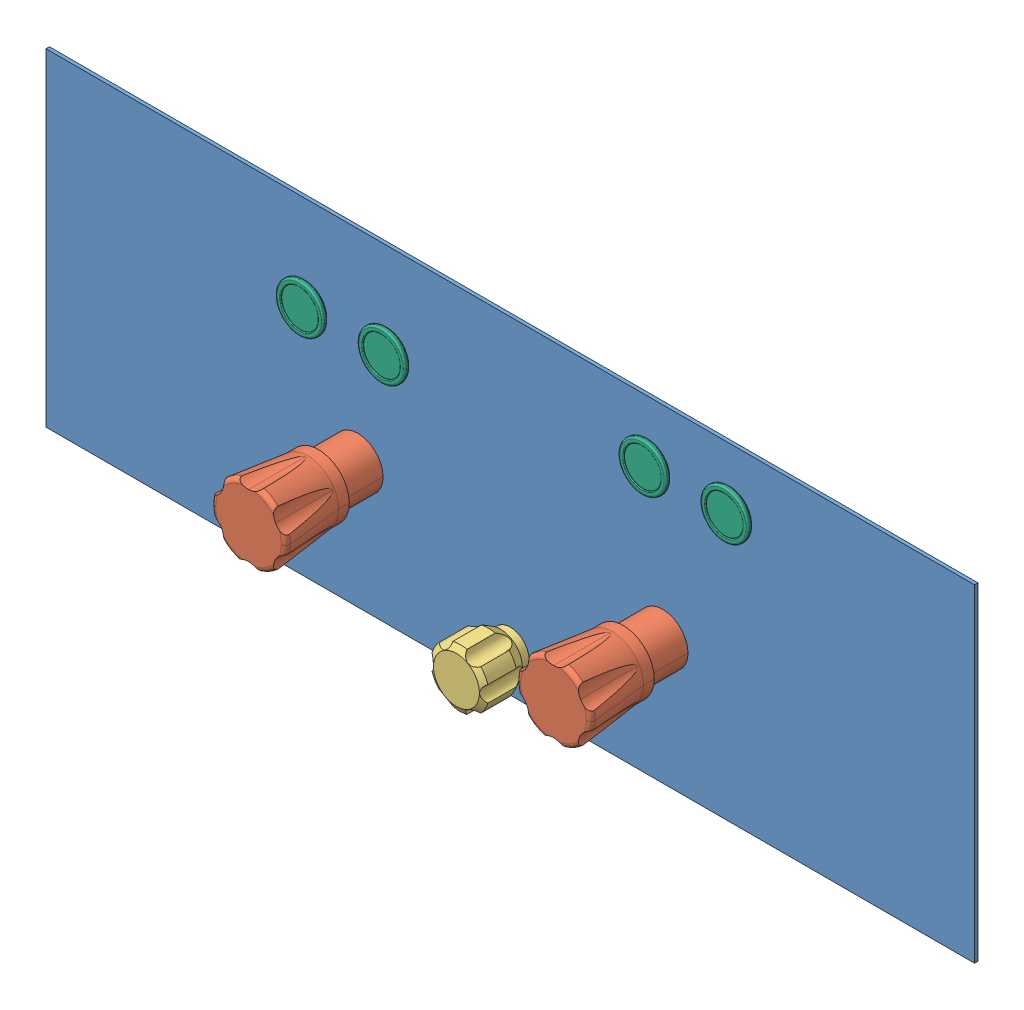
SolidWorks assembly N2_node, configuration Default. Lengths in mm.
Overall size (863.6 304.8 263.66).
11 component instances, 6 part files, 17 mates.
Components (placement in the parent):
- Pressure_panel-1: Pressure_panel [Default] at origin size (863.6 304.8 3.17)
- PRV-1&2_RSHN4-02-6-VVK-Swagelok-1: PRV-1&2_RSHN4-02-6-VVK-Swagelok [Default] at (334.7462 82.8227 -125.3) size (72 78.02 230.14)
- PRV-1&2_RSHN4-02-6-VVK-Swagelok-2: PRV-1&2_RSHN4-02-6-VVK-Swagelok [Default] at (51.1462 82.8227 -125.3) size (72 78.02 230.14)
- KCY1JPA412A20000_PRT_29-1: KCY1JPA412A20000_PRT_29 [Default] at (192.9462 3.5881 -158.828) x (0 1 0) z (0 0 1) size (56.39 55.88 212.09)
- SS-2650-08-08-08-08-1: SS-2650-08-08-08-08 [5482K249] at (192.9462 82.8227 -72.214) size (61.9 61.9 22)
- SS-2404-08-08-1: SS-2404-08-08 [5482K114] at (93.3616 82.8227 -72.214) x (1 0 0) z (0 0.999804 0.019774) size (38.48 23.83 20.64)
- SS-2404-08-08-2: SS-2404-08-08 [5482K114] at (292.5308 82.8227 -72.214) x (-1 0 0) z (0 -0.116154 -0.993231) size (38.48 23.83 20.64)
- 9780T219_VIBRATION-RESISTANT PRESSURE GAUGE-1: 9780T219_VIBRATION-RESISTANT PRESSURE GAUGE [9780T219] at (2.0529 184.7975 8.636) x (0.999997 0.002285 0) z (0 0 1) size (44.45 61.91 48.07)
- 9780T219_VIBRATION-RESISTANT PRESSURE GAUGE-3: 9780T219_VIBRATION-RESISTANT PRESSURE GAUGE [9780T219] at (320.8697 216.2141 8.636) x (-0.158074 0.987427 0) z (0 0 1) size (44.45 61.91 48.07)
- 9780T219_VIBRATION-RESISTANT PRESSURE GAUGE-2: 9780T219_VIBRATION-RESISTANT PRESSURE GAUGE [9780T219] at (78.2529 184.7975 8.636) x (0.999997 0.002285 0) z (0 0 1) size (44.45 61.91 48.07)
- 9780T219_VIBRATION-RESISTANT PRESSURE GAUGE-4: 9780T219_VIBRATION-RESISTANT PRESSURE GAUGE [9780T219] at (397.0697 216.2141 8.636) x (-0.158074 0.987427 0) z (0 0 1) size (44.45 61.91 48.07)
Mates (geometry in assembly coordinates):
- Distance1: distance = 25.4 mm anti-aligned: plane of Pressure_panel-1 through (0 0 0) normal (0 0 -1); plane of PRV-1&2_RSHN4-02-6-VVK-Swagelok-1 through (334.7462 82.8227 -25.4) normal (0 0 1)
- Parallel6: parallel: line of Pressure_panel-1 through (304.8 -238.8538 271.0227) axis (0 0 -1); plane of PRV-1&2_RSHN4-02-6-VVK-Swagelok-1 through (298.7462 82.8227 -0.088) normal (-1 0 0)
- Parallel7: parallel aligned: plane of Pressure_panel-1 through (-238.8538 271.0227 3.175) normal (-1 0 0); plane of PRV-1&2_RSHN4-02-6-VVK-Swagelok-2 through (15.1462 82.8227 -0.088) normal (-1 0 0)
- Distance3: distance = 254 mm aligned: plane of PRV-1&2_RSHN4-02-6-VVK-Swagelok-2 through (15.1462 82.8227 -0.088) normal (-1 0 0); plane of Pressure_panel-1 through (-238.8538 271.0227 3.175) normal (-1 0 0)
- Distance4: distance = 254 mm aligned: plane of PRV-1&2_RSHN4-02-6-VVK-Swagelok-1 through (370.7462 82.8227 -0.088) normal (1 0 0); plane of Pressure_panel-1 through (624.7462 271.0227 3.175) normal (1 0 0)
- Concentric1: concentric anti-aligned: cone of PRV-1&2_RSHN4-02-6-VVK-Swagelok-1 through (306.2575 82.8227 -72.214) axis (1 0 0); cylinder of SS-2650-08-08-08-08-1 through (223.8961 82.8227 -72.214) axis (-1 0 0) radius 4.9657
- Concentric5: concentric aligned: cone of KCY1JPA412A20000_PRT_29-1 through (192.9462 27.4411 -72.214) axis (0 -1 0); cylinder of SS-2650-08-08-08-08-1 through (192.9462 113.7726 -72.214) axis (0 -1 0) radius 4.9657
- Parallel10: parallel aligned: plane of Pressure_panel-1 through (0 0 3.175) normal (0 0 1); plane of KCY1JPA412A20000_PRT_29-1 through (192.9462 14.2881 53.262) normal (0 0 1)
- Concentric7: concentric aligned: cone of PRV-1&2_RSHN4-02-6-VVK-Swagelok-2 through (79.6349 82.8227 -72.214) axis (-1 0 0); cylinder of SS-2650-08-08-08-08-1 through (223.8961 82.8227 -72.214) axis (-1 0 0) radius 4.9657
- Concentric8: concentric anti-aligned: cone of PRV-1&2_RSHN4-02-6-VVK-Swagelok-2 through (79.6349 82.8227 -72.214) axis (-1 0 0); cylinder of SS-2404-08-08-1 through (112.4116 82.8227 -72.214) axis (1 0 0) radius 4.9657
- Coincident18: coincident anti-aligned: plane of PRV-1&2_RSHN4-02-6-VVK-Swagelok-2 through (87.1462 82.8227 -0.088) normal (1 0 0); plane of SS-2404-08-08-1 through (87.1462 72.6238 -78.3744) normal (-1 0 0)
- Concentric9: concentric aligned: cone of PRV-1&2_RSHN4-02-6-VVK-Swagelok-1 through (306.2575 82.8227 -72.214) axis (1 0 0); cylinder of SS-2404-08-08-2 through (298.7462 82.8227 -72.214) axis (1 0 0) radius 6.36
- Coincident19: coincident anti-aligned: plane of PRV-1&2_RSHN4-02-6-VVK-Swagelok-1 through (298.7462 82.8227 -0.088) normal (-1 0 0); plane of SS-2404-08-08-2 through (298.7462 89.9385 -62.6571) normal (1 0 0)
- Distance7: distance = 101.6 mm: line of PRV-1&2_RSHN4-02-6-VVK-Swagelok-2 through (15.1462 67.8227 -40) axis (0 0 -1); plane of Pressure_panel-1 through (-238.8538 -33.7773 3.175) normal (0 -1 0)
- Coincident22: coincident: line of Pressure_panel-1 through (304.8 192.9462 271.0227) axis (0 0 -1); plane of SS-2650-08-08-08-08-1 through (192.9462 82.8227 -72.214) normal (1 0 0)
- Coincident23: coincident anti-aligned: plane of Pressure_panel-1 through (0 0 3.175) normal (0 0 1); circle of 9780T219_VIBRATION-RESISTANT PRESSURE GAUGE-1
- Coincident24: coincident anti-aligned: plane of Pressure_panel-1 through (0 0 3.175) normal (0 0 1); circle of 9780T219_VIBRATION-RESISTANT PRESSURE GAUGE-3
